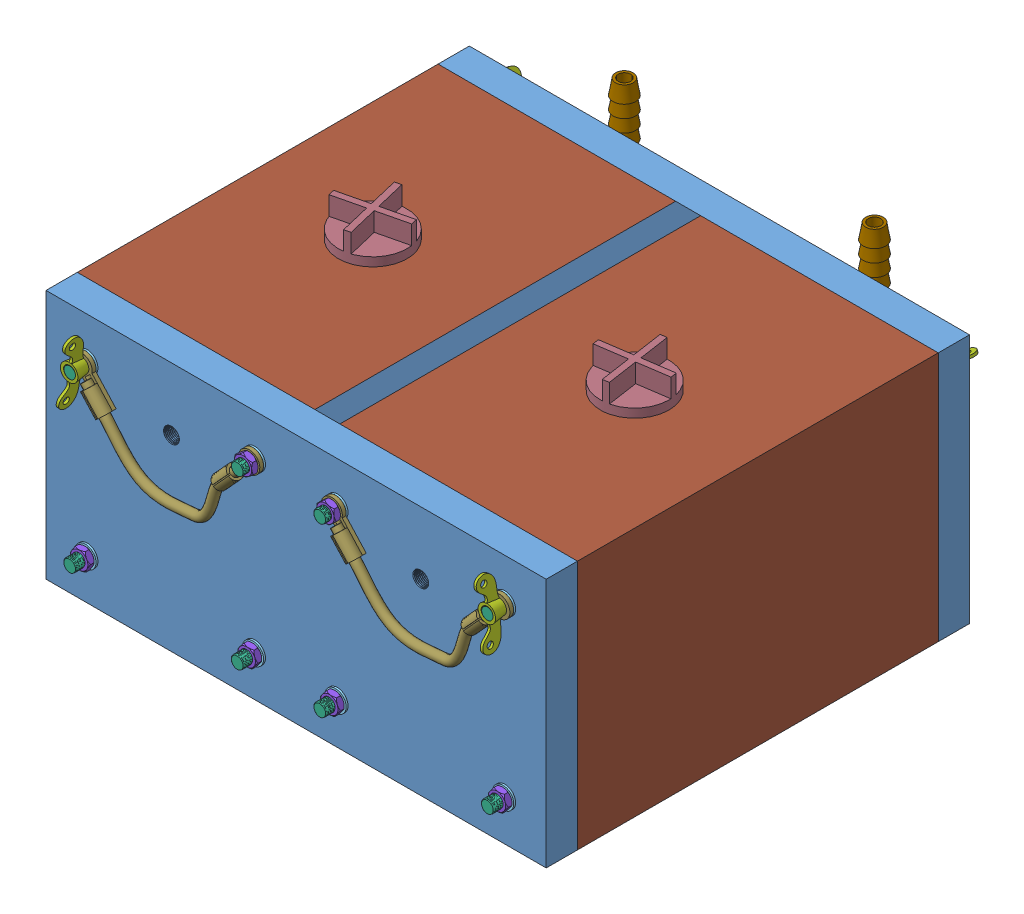
SolidWorks assembly Ventilator, configuration Default. Lengths in mm.
Overall size (400 222 393.22).
352 component instances, 13 part files, 106 mates.
Components (placement in the parent):
- Glass-1: Glass [Default] at (153.2199 -57.0551 297.1136) size (400 200 26.12)
- All Battery Block-1: All Battery Block [Default] at (-10.6585 129.0849 -81.5684) size (150 150 287)
  - Block Battery-1: Block Battery [Default] at (-175.922 -206.6429 -286.6039) size (150 150 40)
    - Gasket-12: Gasket [Default] at (244.3004 275.7985 390.286) size (150 150 3)
    - Plate-1-7: Plate-1 [Default] at (239.8004 279.4658 389.286) size (150 150 1)
    - Gasket-13: Gasket [Default] at (244.3004 275.7985 386.286) size (150 150 3)
    - Plate-1-8: Plate-1 [Default] at (239.8004 279.4658 385.286) size (150 150 1)
    - Gasket-14: Gasket [Default] at (244.3004 275.7985 382.286) size (150 150 3)
    - Plate-2-4: Plate-2 [Default] at (239.8004 279.4658 381.286) size (150 150 1)
    - Plate-1-10: Plate-1 [Default] at (239.8004 279.4658 393.286) size (150 150 1)
    - Gasket-16: Gasket [Default] at (244.3004 275.7985 394.286) size (150 150 3)
    - Plate-1-11: Plate-1 [Default] at (239.8004 279.4658 397.286) size (150 150 1)
    - Gasket-17: Gasket [Default] at (244.3004 275.7985 398.286) size (150 150 3)
    - Plate-2-5: Plate-2 [Default] at (239.8004 279.4658 402.286) x (-1 0 0) z (0 0 -1) size (150 150 1)
    - Gasket-18: Gasket [Default] at (244.3004 275.7985 402.286) size (150 150 3)
    - Plate-1-12: Plate-1 [Default] at (239.8004 279.4658 405.286) size (150 150 1)
    - Gasket-19: Gasket [Default] at (244.3004 275.7985 406.286) size (150 150 3)
    - Plate-1-13: Plate-1 [Default] at (239.8004 279.4658 409.286) size (150 150 1)
    - Gasket-20: Gasket [Default] at (244.3004 275.7985 410.286) size (150 150 3)
    - Plate-1-14: Plate-1 [Default] at (239.8004 279.4658 413.286) size (150 150 1)
    - Gasket-21: Gasket [Default] at (244.3004 275.7985 414.286) size (150 150 3)
    - Plate-1-15: Plate-1 [Default] at (239.8004 279.4658 417.286) size (150 150 1)
    - Gasket-22: Gasket [Default] at (244.3004 275.7985 418.286) size (150 150 3)
  - Block Battery-2: Block Battery [Default] at (-175.922 -206.6429 -246.6039) size (150 150 40)
    - Gasket-12: Gasket [Default] at (244.3004 275.7985 390.286) size (150 150 3)
    - Plate-1-7: Plate-1 [Default] at (239.8004 279.4658 389.286) size (150 150 1)
    - Gasket-13: Gasket [Default] at (244.3004 275.7985 386.286) size (150 150 3)
    - Plate-1-8: Plate-1 [Default] at (239.8004 279.4658 385.286) size (150 150 1)
    - Gasket-14: Gasket [Default] at (244.3004 275.7985 382.286) size (150 150 3)
    - Plate-2-4: Plate-2 [Default] at (239.8004 279.4658 381.286) size (150 150 1)
    - Plate-1-10: Plate-1 [Default] at (239.8004 279.4658 393.286) size (150 150 1)
    - Gasket-16: Gasket [Default] at (244.3004 275.7985 394.286) size (150 150 3)
    - Plate-1-11: Plate-1 [Default] at (239.8004 279.4658 397.286) size (150 150 1)
    - Gasket-17: Gasket [Default] at (244.3004 275.7985 398.286) size (150 150 3)
    - Plate-2-5: Plate-2 [Default] at (239.8004 279.4658 402.286) x (-1 0 0) z (0 0 -1) size (150 150 1)
    - Gasket-18: Gasket [Default] at (244.3004 275.7985 402.286) size (150 150 3)
    - Plate-1-12: Plate-1 [Default] at (239.8004 279.4658 405.286) size (150 150 1)
    - Gasket-19: Gasket [Default] at (244.3004 275.7985 406.286) size (150 150 3)
    - Plate-1-13: Plate-1 [Default] at (239.8004 279.4658 409.286) size (150 150 1)
    - Gasket-20: Gasket [Default] at (244.3004 275.7985 410.286) size (150 150 3)
    - Plate-1-14: Plate-1 [Default] at (239.8004 279.4658 413.286) size (150 150 1)
    - Gasket-21: Gasket [Default] at (244.3004 275.7985 414.286) size (150 150 3)
    - Plate-1-15: Plate-1 [Default] at (239.8004 279.4658 417.286) size (150 150 1)
    - Gasket-22: Gasket [Default] at (244.3004 275.7985 418.286) size (150 150 3)
  - Block Battery-3: Block Battery [Default] at (-175.922 -206.6429 -206.6039) size (150 150 40)
    - Gasket-12: Gasket [Default] at (244.3004 275.7985 390.286) size (150 150 3)
    - Plate-1-7: Plate-1 [Default] at (239.8004 279.4658 389.286) size (150 150 1)
    - Gasket-13: Gasket [Default] at (244.3004 275.7985 386.286) size (150 150 3)
    - Plate-1-8: Plate-1 [Default] at (239.8004 279.4658 385.286) size (150 150 1)
    - Gasket-14: Gasket [Default] at (244.3004 275.7985 382.286) size (150 150 3)
    - Plate-2-4: Plate-2 [Default] at (239.8004 279.4658 381.286) size (150 150 1)
    - Plate-1-10: Plate-1 [Default] at (239.8004 279.4658 393.286) size (150 150 1)
    - Gasket-16: Gasket [Default] at (244.3004 275.7985 394.286) size (150 150 3)
    - Plate-1-11: Plate-1 [Default] at (239.8004 279.4658 397.286) size (150 150 1)
    - Gasket-17: Gasket [Default] at (244.3004 275.7985 398.286) size (150 150 3)
    - Plate-2-5: Plate-2 [Default] at (239.8004 279.4658 402.286) x (-1 0 0) z (0 0 -1) size (150 150 1)
    - Gasket-18: Gasket [Default] at (244.3004 275.7985 402.286) size (150 150 3)
    - Plate-1-12: Plate-1 [Default] at (239.8004 279.4658 405.286) size (150 150 1)
    - Gasket-19: Gasket [Default] at (244.3004 275.7985 406.286) size (150 150 3)
    - Plate-1-13: Plate-1 [Default] at (239.8004 279.4658 409.286) size (150 150 1)
    - Gasket-20: Gasket [Default] at (244.3004 275.7985 410.286) size (150 150 3)
    - Plate-1-14: Plate-1 [Default] at (239.8004 279.4658 413.286) size (150 150 1)
    - Gasket-21: Gasket [Default] at (244.3004 275.7985 414.286) size (150 150 3)
    - Plate-1-15: Plate-1 [Default] at (239.8004 279.4658 417.286) size (150 150 1)
    - Gasket-22: Gasket [Default] at (244.3004 275.7985 418.286) size (150 150 3)
  - Block Battery-4: Block Battery [Default] at (-175.922 -206.6429 -166.6039) size (150 150 40)
    - Gasket-12: Gasket [Default] at (244.3004 275.7985 390.286) size (150 150 3)
    - Plate-1-7: Plate-1 [Default] at (239.8004 279.4658 389.286) size (150 150 1)
    - Gasket-13: Gasket [Default] at (244.3004 275.7985 386.286) size (150 150 3)
    - Plate-1-8: Plate-1 [Default] at (239.8004 279.4658 385.286) size (150 150 1)
    - Gasket-14: Gasket [Default] at (244.3004 275.7985 382.286) size (150 150 3)
    - Plate-2-4: Plate-2 [Default] at (239.8004 279.4658 381.286) size (150 150 1)
    - Plate-1-10: Plate-1 [Default] at (239.8004 279.4658 393.286) size (150 150 1)
    - Gasket-16: Gasket [Default] at (244.3004 275.7985 394.286) size (150 150 3)
    - Plate-1-11: Plate-1 [Default] at (239.8004 279.4658 397.286) size (150 150 1)
    - Gasket-17: Gasket [Default] at (244.3004 275.7985 398.286) size (150 150 3)
    - Plate-2-5: Plate-2 [Default] at (239.8004 279.4658 402.286) x (-1 0 0) z (0 0 -1) size (150 150 1)
    - Gasket-18: Gasket [Default] at (244.3004 275.7985 402.286) size (150 150 3)
    - Plate-1-12: Plate-1 [Default] at (239.8004 279.4658 405.286) size (150 150 1)
    - Gasket-19: Gasket [Default] at (244.3004 275.7985 406.286) size (150 150 3)
    - Plate-1-13: Plate-1 [Default] at (239.8004 279.4658 409.286) size (150 150 1)
    - Gasket-20: Gasket [Default] at (244.3004 275.7985 410.286) size (150 150 3)
    - Plate-1-14: Plate-1 [Default] at (239.8004 279.4658 413.286) size (150 150 1)
    - Gasket-21: Gasket [Default] at (244.3004 275.7985 414.286) size (150 150 3)
    - Plate-1-15: Plate-1 [Default] at (239.8004 279.4658 417.286) size (150 150 1)
    - Gasket-22: Gasket [Default] at (244.3004 275.7985 418.286) size (150 150 3)
  - Block Battery-5: Block Battery [Default] at (-175.922 -206.6429 -126.6039) size (150 150 40)
    - Gasket-12: Gasket [Default] at (244.3004 275.7985 390.286) size (150 150 3)
    - Plate-1-7: Plate-1 [Default] at (239.8004 279.4658 389.286) size (150 150 1)
    - Gasket-13: Gasket [Default] at (244.3004 275.7985 386.286) size (150 150 3)
    - Plate-1-8: Plate-1 [Default] at (239.8004 279.4658 385.286) size (150 150 1)
    - Gasket-14: Gasket [Default] at (244.3004 275.7985 382.286) size (150 150 3)
    - Plate-2-4: Plate-2 [Default] at (239.8004 279.4658 381.286) size (150 150 1)
    - Plate-1-10: Plate-1 [Default] at (239.8004 279.4658 393.286) size (150 150 1)
    - Gasket-16: Gasket [Default] at (244.3004 275.7985 394.286) size (150 150 3)
    - Plate-1-11: Plate-1 [Default] at (239.8004 279.4658 397.286) size (150 150 1)
    - Gasket-17: Gasket [Default] at (244.3004 275.7985 398.286) size (150 150 3)
    - Plate-2-5: Plate-2 [Default] at (239.8004 279.4658 402.286) x (-1 0 0) z (0 0 -1) size (150 150 1)
    - Gasket-18: Gasket [Default] at (244.3004 275.7985 402.286) size (150 150 3)
    - Plate-1-12: Plate-1 [Default] at (239.8004 279.4658 405.286) size (150 150 1)
    - Gasket-19: Gasket [Default] at (244.3004 275.7985 406.286) size (150 150 3)
    - Plate-1-13: Plate-1 [Default] at (239.8004 279.4658 409.286) size (150 150 1)
    - Gasket-20: Gasket [Default] at (244.3004 275.7985 410.286) size (150 150 3)
    - Plate-1-14: Plate-1 [Default] at (239.8004 279.4658 413.286) size (150 150 1)
    - Gasket-21: Gasket [Default] at (244.3004 275.7985 414.286) size (150 150 3)
    - Plate-1-15: Plate-1 [Default] at (239.8004 279.4658 417.286) size (150 150 1)
    - Gasket-22: Gasket [Default] at (244.3004 275.7985 418.286) size (150 150 3)
  - Block Battery-6: Block Battery [Default] at (-175.922 -206.6429 -86.6039) size (150 150 40)
    - Gasket-12: Gasket [Default] at (244.3004 275.7985 390.286) size (150 150 3)
    - Plate-1-7: Plate-1 [Default] at (239.8004 279.4658 389.286) size (150 150 1)
    - Gasket-13: Gasket [Default] at (244.3004 275.7985 386.286) size (150 150 3)
    - Plate-1-8: Plate-1 [Default] at (239.8004 279.4658 385.286) size (150 150 1)
    - Gasket-14: Gasket [Default] at (244.3004 275.7985 382.286) size (150 150 3)
    - Plate-2-4: Plate-2 [Default] at (239.8004 279.4658 381.286) size (150 150 1)
    - Plate-1-10: Plate-1 [Default] at (239.8004 279.4658 393.286) size (150 150 1)
    - Gasket-16: Gasket [Default] at (244.3004 275.7985 394.286) size (150 150 3)
    - Plate-1-11: Plate-1 [Default] at (239.8004 279.4658 397.286) size (150 150 1)
    - Gasket-17: Gasket [Default] at (244.3004 275.7985 398.286) size (150 150 3)
    - Plate-2-5: Plate-2 [Default] at (239.8004 279.4658 402.286) x (-1 0 0) z (0 0 -1) size (150 150 1)
    - Gasket-18: Gasket [Default] at (244.3004 275.7985 402.286) size (150 150 3)
    - Plate-1-12: Plate-1 [Default] at (239.8004 279.4658 405.286) size (150 150 1)
    - Gasket-19: Gasket [Default] at (244.3004 275.7985 406.286) size (150 150 3)
    - Plate-1-13: Plate-1 [Default] at (239.8004 279.4658 409.286) size (150 150 1)
    - Gasket-20: Gasket [Default] at (244.3004 275.7985 410.286) size (150 150 3)
    - Plate-1-14: Plate-1 [Default] at (239.8004 279.4658 413.286) size (150 150 1)
    - Gasket-21: Gasket [Default] at (244.3004 275.7985 414.286) size (150 150 3)
    - Plate-1-15: Plate-1 [Default] at (239.8004 279.4658 417.286) size (150 150 1)
    - Gasket-22: Gasket [Default] at (244.3004 275.7985 418.286) size (150 150 3)
  - Block Battery-7: Block Battery [Default] at (-175.922 -206.6429 -46.6039) size (150 150 40)
    - Gasket-12: Gasket [Default] at (244.3004 275.7985 390.286) size (150 150 3)
    - Plate-1-7: Plate-1 [Default] at (239.8004 279.4658 389.286) size (150 150 1)
    - Gasket-13: Gasket [Default] at (244.3004 275.7985 386.286) size (150 150 3)
    - Plate-1-8: Plate-1 [Default] at (239.8004 279.4658 385.286) size (150 150 1)
    - Gasket-14: Gasket [Default] at (244.3004 275.7985 382.286) size (150 150 3)
    - Plate-2-4: Plate-2 [Default] at (239.8004 279.4658 381.286) size (150 150 1)
    - Plate-1-10: Plate-1 [Default] at (239.8004 279.4658 393.286) size (150 150 1)
    - Gasket-16: Gasket [Default] at (244.3004 275.7985 394.286) size (150 150 3)
    - Plate-1-11: Plate-1 [Default] at (239.8004 279.4658 397.286) size (150 150 1)
    - Gasket-17: Gasket [Default] at (244.3004 275.7985 398.286) size (150 150 3)
    - Plate-2-5: Plate-2 [Default] at (239.8004 279.4658 402.286) x (-1 0 0) z (0 0 -1) size (150 150 1)
    - Gasket-18: Gasket [Default] at (244.3004 275.7985 402.286) size (150 150 3)
    - Plate-1-12: Plate-1 [Default] at (239.8004 279.4658 405.286) size (150 150 1)
    - Gasket-19: Gasket [Default] at (244.3004 275.7985 406.286) size (150 150 3)
    - Plate-1-13: Plate-1 [Default] at (239.8004 279.4658 409.286) size (150 150 1)
    - Gasket-20: Gasket [Default] at (244.3004 275.7985 410.286) size (150 150 3)
    - Plate-1-14: Plate-1 [Default] at (239.8004 279.4658 413.286) size (150 150 1)
    - Gasket-21: Gasket [Default] at (244.3004 275.7985 414.286) size (150 150 3)
    - Plate-1-15: Plate-1 [Default] at (239.8004 279.4658 417.286) size (150 150 1)
    - Gasket-22: Gasket [Default] at (244.3004 275.7985 418.286) size (150 150 3)
  - Plate-2-1: Plate-2 [Default] at (63.8784 72.8229 374.682) size (150 150 1)
  - Gasket-1: Gasket [Default] at (68.3784 69.1556 375.682) size (150 150 3)
  - Gasket-2: Gasket [Default] at (68.3784 69.1556 91.682) size (150 150 3)
- All Battery Block-2: All Battery Block [Default] at (189.3415 129.0849 -81.5684) size (150 150 287)
  - Block Battery-1: Block Battery [Default] at (-175.922 -206.6429 -286.6039) size (150 150 40)
    - Gasket-12: Gasket [Default] at (244.3004 275.7985 390.286) size (150 150 3)
    - Plate-1-7: Plate-1 [Default] at (239.8004 279.4658 389.286) size (150 150 1)
    - Gasket-13: Gasket [Default] at (244.3004 275.7985 386.286) size (150 150 3)
    - Plate-1-8: Plate-1 [Default] at (239.8004 279.4658 385.286) size (150 150 1)
    - Gasket-14: Gasket [Default] at (244.3004 275.7985 382.286) size (150 150 3)
    - Plate-2-4: Plate-2 [Default] at (239.8004 279.4658 381.286) size (150 150 1)
    - Plate-1-10: Plate-1 [Default] at (239.8004 279.4658 393.286) size (150 150 1)
    - Gasket-16: Gasket [Default] at (244.3004 275.7985 394.286) size (150 150 3)
    - Plate-1-11: Plate-1 [Default] at (239.8004 279.4658 397.286) size (150 150 1)
    - Gasket-17: Gasket [Default] at (244.3004 275.7985 398.286) size (150 150 3)
    - Plate-2-5: Plate-2 [Default] at (239.8004 279.4658 402.286) x (-1 0 0) z (0 0 -1) size (150 150 1)
    - Gasket-18: Gasket [Default] at (244.3004 275.7985 402.286) size (150 150 3)
    - Plate-1-12: Plate-1 [Default] at (239.8004 279.4658 405.286) size (150 150 1)
    - Gasket-19: Gasket [Default] at (244.3004 275.7985 406.286) size (150 150 3)
    - Plate-1-13: Plate-1 [Default] at (239.8004 279.4658 409.286) size (150 150 1)
    - Gasket-20: Gasket [Default] at (244.3004 275.7985 410.286) size (150 150 3)
    - Plate-1-14: Plate-1 [Default] at (239.8004 279.4658 413.286) size (150 150 1)
    - Gasket-21: Gasket [Default] at (244.3004 275.7985 414.286) size (150 150 3)
    - Plate-1-15: Plate-1 [Default] at (239.8004 279.4658 417.286) size (150 150 1)
    - Gasket-22: Gasket [Default] at (244.3004 275.7985 418.286) size (150 150 3)
  - Block Battery-2: Block Battery [Default] at (-175.922 -206.6429 -246.6039) size (150 150 40)
    - Gasket-12: Gasket [Default] at (244.3004 275.7985 390.286) size (150 150 3)
    - Plate-1-7: Plate-1 [Default] at (239.8004 279.4658 389.286) size (150 150 1)
    - Gasket-13: Gasket [Default] at (244.3004 275.7985 386.286) size (150 150 3)
    - Plate-1-8: Plate-1 [Default] at (239.8004 279.4658 385.286) size (150 150 1)
    - Gasket-14: Gasket [Default] at (244.3004 275.7985 382.286) size (150 150 3)
    - Plate-2-4: Plate-2 [Default] at (239.8004 279.4658 381.286) size (150 150 1)
    - Plate-1-10: Plate-1 [Default] at (239.8004 279.4658 393.286) size (150 150 1)
    - Gasket-16: Gasket [Default] at (244.3004 275.7985 394.286) size (150 150 3)
    - Plate-1-11: Plate-1 [Default] at (239.8004 279.4658 397.286) size (150 150 1)
    - Gasket-17: Gasket [Default] at (244.3004 275.7985 398.286) size (150 150 3)
    - Plate-2-5: Plate-2 [Default] at (239.8004 279.4658 402.286) x (-1 0 0) z (0 0 -1) size (150 150 1)
    - Gasket-18: Gasket [Default] at (244.3004 275.7985 402.286) size (150 150 3)
    - Plate-1-12: Plate-1 [Default] at (239.8004 279.4658 405.286) size (150 150 1)
    - Gasket-19: Gasket [Default] at (244.3004 275.7985 406.286) size (150 150 3)
    - Plate-1-13: Plate-1 [Default] at (239.8004 279.4658 409.286) size (150 150 1)
    - Gasket-20: Gasket [Default] at (244.3004 275.7985 410.286) size (150 150 3)
    - Plate-1-14: Plate-1 [Default] at (239.8004 279.4658 413.286) size (150 150 1)
    - Gasket-21: Gasket [Default] at (244.3004 275.7985 414.286) size (150 150 3)
    - Plate-1-15: Plate-1 [Default] at (239.8004 279.4658 417.286) size (150 150 1)
    - Gasket-22: Gasket [Default] at (244.3004 275.7985 418.286) size (150 150 3)
  - Block Battery-3: Block Battery [Default] at (-175.922 -206.6429 -206.6039) size (150 150 40)
    - Gasket-12: Gasket [Default] at (244.3004 275.7985 390.286) size (150 150 3)
    - Plate-1-7: Plate-1 [Default] at (239.8004 279.4658 389.286) size (150 150 1)
    - Gasket-13: Gasket [Default] at (244.3004 275.7985 386.286) size (150 150 3)
    - Plate-1-8: Plate-1 [Default] at (239.8004 279.4658 385.286) size (150 150 1)
    - Gasket-14: Gasket [Default] at (244.3004 275.7985 382.286) size (150 150 3)
    - Plate-2-4: Plate-2 [Default] at (239.8004 279.4658 381.286) size (150 150 1)
    - Plate-1-10: Plate-1 [Default] at (239.8004 279.4658 393.286) size (150 150 1)
    - Gasket-16: Gasket [Default] at (244.3004 275.7985 394.286) size (150 150 3)
    - Plate-1-11: Plate-1 [Default] at (239.8004 279.4658 397.286) size (150 150 1)
    - Gasket-17: Gasket [Default] at (244.3004 275.7985 398.286) size (150 150 3)
    - Plate-2-5: Plate-2 [Default] at (239.8004 279.4658 402.286) x (-1 0 0) z (0 0 -1) size (150 150 1)
    - Gasket-18: Gasket [Default] at (244.3004 275.7985 402.286) size (150 150 3)
    - Plate-1-12: Plate-1 [Default] at (239.8004 279.4658 405.286) size (150 150 1)
    - Gasket-19: Gasket [Default] at (244.3004 275.7985 406.286) size (150 150 3)
    - Plate-1-13: Plate-1 [Default] at (239.8004 279.4658 409.286) size (150 150 1)
    - Gasket-20: Gasket [Default] at (244.3004 275.7985 410.286) size (150 150 3)
    - Plate-1-14: Plate-1 [Default] at (239.8004 279.4658 413.286) size (150 150 1)
    - Gasket-21: Gasket [Default] at (244.3004 275.7985 414.286) size (150 150 3)
    - Plate-1-15: Plate-1 [Default] at (239.8004 279.4658 417.286) size (150 150 1)
    - Gasket-22: Gasket [Default] at (244.3004 275.7985 418.286) size (150 150 3)
  - Block Battery-4: Block Battery [Default] at (-175.922 -206.6429 -166.6039) size (150 150 40)
    - Gasket-12: Gasket [Default] at (244.3004 275.7985 390.286) size (150 150 3)
    - Plate-1-7: Plate-1 [Default] at (239.8004 279.4658 389.286) size (150 150 1)
    - Gasket-13: Gasket [Default] at (244.3004 275.7985 386.286) size (150 150 3)
    - Plate-1-8: Plate-1 [Default] at (239.8004 279.4658 385.286) size (150 150 1)
    - Gasket-14: Gasket [Default] at (244.3004 275.7985 382.286) size (150 150 3)
    - Plate-2-4: Plate-2 [Default] at (239.8004 279.4658 381.286) size (150 150 1)
    - Plate-1-10: Plate-1 [Default] at (239.8004 279.4658 393.286) size (150 150 1)
    - Gasket-16: Gasket [Default] at (244.3004 275.7985 394.286) size (150 150 3)
    - Plate-1-11: Plate-1 [Default] at (239.8004 279.4658 397.286) size (150 150 1)
    - Gasket-17: Gasket [Default] at (244.3004 275.7985 398.286) size (150 150 3)
    - Plate-2-5: Plate-2 [Default] at (239.8004 279.4658 402.286) x (-1 0 0) z (0 0 -1) size (150 150 1)
    - Gasket-18: Gasket [Default] at (244.3004 275.7985 402.286) size (150 150 3)
    - Plate-1-12: Plate-1 [Default] at (239.8004 279.4658 405.286) size (150 150 1)
    - Gasket-19: Gasket [Default] at (244.3004 275.7985 406.286) size (150 150 3)
    - Plate-1-13: Plate-1 [Default] at (239.8004 279.4658 409.286) size (150 150 1)
    - Gasket-20: Gasket [Default] at (244.3004 275.7985 410.286) size (150 150 3)
    - Plate-1-14: Plate-1 [Default] at (239.8004 279.4658 413.286) size (150 150 1)
    - Gasket-21: Gasket [Default] at (244.3004 275.7985 414.286) size (150 150 3)
    - Plate-1-15: Plate-1 [Default] at (239.8004 279.4658 417.286) size (150 150 1)
    - Gasket-22: Gasket [Default] at (244.3004 275.7985 418.286) size (150 150 3)
  - Block Battery-5: Block Battery [Default] at (-175.922 -206.6429 -126.6039) size (150 150 40)
    - Gasket-12: Gasket [Default] at (244.3004 275.7985 390.286) size (150 150 3)
    - Plate-1-7: Plate-1 [Default] at (239.8004 279.4658 389.286) size (150 150 1)
    - Gasket-13: Gasket [Default] at (244.3004 275.7985 386.286) size (150 150 3)
    - Plate-1-8: Plate-1 [Default] at (239.8004 279.4658 385.286) size (150 150 1)
    - Gasket-14: Gasket [Default] at (244.3004 275.7985 382.286) size (150 150 3)
    - Plate-2-4: Plate-2 [Default] at (239.8004 279.4658 381.286) size (150 150 1)
    - Plate-1-10: Plate-1 [Default] at (239.8004 279.4658 393.286) size (150 150 1)
    - Gasket-16: Gasket [Default] at (244.3004 275.7985 394.286) size (150 150 3)
    - Plate-1-11: Plate-1 [Default] at (239.8004 279.4658 397.286) size (150 150 1)
    - Gasket-17: Gasket [Default] at (244.3004 275.7985 398.286) size (150 150 3)
    - Plate-2-5: Plate-2 [Default] at (239.8004 279.4658 402.286) x (-1 0 0) z (0 0 -1) size (150 150 1)
    - Gasket-18: Gasket [Default] at (244.3004 275.7985 402.286) size (150 150 3)
    - Plate-1-12: Plate-1 [Default] at (239.8004 279.4658 405.286) size (150 150 1)
    - Gasket-19: Gasket [Default] at (244.3004 275.7985 406.286) size (150 150 3)
    - Plate-1-13: Plate-1 [Default] at (239.8004 279.4658 409.286) size (150 150 1)
    - Gasket-20: Gasket [Default] at (244.3004 275.7985 410.286) size (150 150 3)
    - Plate-1-14: Plate-1 [Default] at (239.8004 279.4658 413.286) size (150 150 1)
    - Gasket-21: Gasket [Default] at (244.3004 275.7985 414.286) size (150 150 3)
    - Plate-1-15: Plate-1 [Default] at (239.8004 279.4658 417.286) size (150 150 1)
    - Gasket-22: Gasket [Default] at (244.3004 275.7985 418.286) size (150 150 3)
  - Block Battery-6: Block Battery [Default] at (-175.922 -206.6429 -86.6039) size (150 150 40)
    - Gasket-12: Gasket [Default] at (244.3004 275.7985 390.286) size (150 150 3)
    - Plate-1-7: Plate-1 [Default] at (239.8004 279.4658 389.286) size (150 150 1)
    - Gasket-13: Gasket [Default] at (244.3004 275.7985 386.286) size (150 150 3)
    - Plate-1-8: Plate-1 [Default] at (239.8004 279.4658 385.286) size (150 150 1)
    - Gasket-14: Gasket [Default] at (244.3004 275.7985 382.286) size (150 150 3)
    - Plate-2-4: Plate-2 [Default] at (239.8004 279.4658 381.286) size (150 150 1)
    - Plate-1-10: Plate-1 [Default] at (239.8004 279.4658 393.286) size (150 150 1)
    - Gasket-16: Gasket [Default] at (244.3004 275.7985 394.286) size (150 150 3)
    - Plate-1-11: Plate-1 [Default] at (239.8004 279.4658 397.286) size (150 150 1)
    - Gasket-17: Gasket [Default] at (244.3004 275.7985 398.286) size (150 150 3)
    - Plate-2-5: Plate-2 [Default] at (239.8004 279.4658 402.286) x (-1 0 0) z (0 0 -1) size (150 150 1)
    - Gasket-18: Gasket [Default] at (244.3004 275.7985 402.286) size (150 150 3)
    - Plate-1-12: Plate-1 [Default] at (239.8004 279.4658 405.286) size (150 150 1)
    - Gasket-19: Gasket [Default] at (244.3004 275.7985 406.286) size (150 150 3)
    - Plate-1-13: Plate-1 [Default] at (239.8004 279.4658 409.286) size (150 150 1)
    - Gasket-20: Gasket [Default] at (244.3004 275.7985 410.286) size (150 150 3)
    - Plate-1-14: Plate-1 [Default] at (239.8004 279.4658 413.286) size (150 150 1)
    - Gasket-21: Gasket [Default] at (244.3004 275.7985 414.286) size (150 150 3)
    - Plate-1-15: Plate-1 [Default] at (239.8004 279.4658 417.286) size (150 150 1)
    - Gasket-22: Gasket [Default] at (244.3004 275.7985 418.286) size (150 150 3)
  - Block Battery-7: Block Battery [Default] at (-175.922 -206.6429 -46.6039) size (150 150 40)
    - Gasket-12: Gasket [Default] at (244.3004 275.7985 390.286) size (150 150 3)
    - Plate-1-7: Plate-1 [Default] at (239.8004 279.4658 389.286) size (150 150 1)
    - Gasket-13: Gasket [Default] at (244.3004 275.7985 386.286) size (150 150 3)
    - Plate-1-8: Plate-1 [Default] at (239.8004 279.4658 385.286) size (150 150 1)
    - Gasket-14: Gasket [Default] at (244.3004 275.7985 382.286) size (150 150 3)
    - Plate-2-4: Plate-2 [Default] at (239.8004 279.4658 381.286) size (150 150 1)
    - Plate-1-10: Plate-1 [Default] at (239.8004 279.4658 393.286) size (150 150 1)
    - Gasket-16: Gasket [Default] at (244.3004 275.7985 394.286) size (150 150 3)
    - Plate-1-11: Plate-1 [Default] at (239.8004 279.4658 397.286) size (150 150 1)
    - Gasket-17: Gasket [Default] at (244.3004 275.7985 398.286) size (150 150 3)
    - Plate-2-5: Plate-2 [Default] at (239.8004 279.4658 402.286) x (-1 0 0) z (0 0 -1) size (150 150 1)
    - Gasket-18: Gasket [Default] at (244.3004 275.7985 402.286) size (150 150 3)
    - Plate-1-12: Plate-1 [Default] at (239.8004 279.4658 405.286) size (150 150 1)
    - Gasket-19: Gasket [Default] at (244.3004 275.7985 406.286) size (150 150 3)
    - Plate-1-13: Plate-1 [Default] at (239.8004 279.4658 409.286) size (150 150 1)
    - Gasket-20: Gasket [Default] at (244.3004 275.7985 410.286) size (150 150 3)
    - Plate-1-14: Plate-1 [Default] at (239.8004 279.4658 413.286) size (150 150 1)
    - Gasket-21: Gasket [Default] at (244.3004 275.7985 414.286) size (150 150 3)
    - Plate-1-15: Plate-1 [Default] at (239.8004 279.4658 417.286) size (150 150 1)
    - Gasket-22: Gasket [Default] at (244.3004 275.7985 418.286) size (150 150 3)
  - Plate-2-1: Plate-2 [Default] at (63.8784 72.8229 374.682) size (150 150 1)
  - Gasket-1: Gasket [Default] at (68.3784 69.1556 375.682) size (150 150 3)
  - Gasket-2: Gasket [Default] at (68.3784 69.1556 91.682) size (150 150 3)
- Glass-2: Glass [Default] at (153.2199 -57.0551 -16.3864) size (400 200 26.12)
- Washer-1: Washer [Default] at (320.2199 268.9078 -17.8864) size (17 17 1.5)
- Screw-2: Screw [Default] at (-13.7801 268.9078 -30.3864) size (10.01 10.25 367.6)
- Washer-2: Washer [Default] at (-13.7801 268.9078 322.1136) size (17 17 1.5)
- Vint-3: Vint [Default] at (320.2199 268.9078 -27.8864) x (0.941946 0.335764 0) z (0 0 1) size (52.29 14 17.39)
- Washer-3: Washer [Default] at (-13.7801 268.9078 -17.8864) size (17 17 1.5)
- Screw-4: Screw [Default] at (-13.7801 134.9078 -30.3864) size (10.01 10.25 367.6)
- Screw-5: Screw [Default] at (120.2199 268.9078 -30.3864) size (10.01 10.25 367.6)
- Washer-4: Washer [Default] at (120.2199 268.9078 322.1136) size (17 17 1.5)
- Washer-5: Washer [Default] at (-13.7801 134.9078 322.1136) size (17 17 1.5)
- Washer-6: Washer [Default] at (120.2199 268.9078 -17.8864) size (17 17 1.5)
- Washer-7: Washer [Default] at (-13.7801 134.9078 -17.8864) size (17 17 1.5)
- Screw-6: Screw [Default] at (186.2199 268.9078 -30.3864) size (10.01 10.25 367.6)
- Washer-8: Washer [Default] at (186.2199 268.9078 -17.8864) size (17 17 1.5)
- Screw-7: Screw [Default] at (320.2199 268.9078 -30.3864) size (10.01 10.25 367.6)
- Screw-8: Screw [Default] at (320.2199 134.9078 -30.3864) size (10.01 10.25 367.6)
- Screw-9: Screw [Default] at (186.2199 134.9078 -30.3864) size (10.01 10.25 367.6)
- Screw-10: Screw [Default] at (120.2199 134.9078 -30.3864) size (10.01 10.25 367.6)
- Washer-9: Washer [Default] at (320.2199 268.9078 322.1136) size (17 17 1.5)
- Washer-10: Washer [Default] at (320.2199 134.9078 322.1136) size (17 17 1.5)
- Washer-11: Washer [Default] at (186.2199 268.9078 322.1136) size (17 17 1.5)
- Washer-12: Washer [Default] at (186.2199 134.9078 322.1136) size (17 17 1.5)
- Washer-13: Washer [Default] at (120.2199 134.9078 322.1136) size (17 17 1.5)
- Washer-14: Washer [Default] at (320.2199 134.9078 -17.8864) size (17 17 1.5)
- Washer-15: Washer [Default] at (120.2199 134.9078 -17.8864) size (17 17 1.5)
- Washer-16: Washer [Default] at (186.2199 134.9078 -17.8864) size (17 17 1.5)
- Vint-5: Vint [Default] at (-13.7801 268.9078 -27.8864) x (0.551468 -0.834196 0) z (0 0 1) size (52.29 14 17.39)
- Mutter M10-2: Mutter M10 [Default] at (120.2199 268.9078 -22.8864) size (16.8 16.24 6.22)
- Mutter M10-4: Mutter M10 [Default] at (120.2199 134.9078 323.6136) size (16.8 16.24 6.22)
- Mutter M10-5: Mutter M10 [Default] at (186.2199 134.9078 323.6136) size (16.8 16.24 6.22)
- Mutter M10-6: Mutter M10 [Default] at (186.2199 134.9078 -22.8864) size (16.8 16.24 6.22)
- Mutter M10-7: Mutter M10 [Default] at (186.2199 268.9078 -22.8864) size (16.8 16.24 6.22)
- Mutter M10-8: Mutter M10 [Default] at (120.2199 134.9078 -22.8864) size (16.8 16.24 6.22)
- branch pipe-1: branch pipe [Default] at (53.2199 251.9078 -32.3864) x (-1 0 0) z (0 0 1) size (18.58 74 52.8)
- branch pipe-2: branch pipe [Default] at (253.2199 251.9078 -32.3864) x (-1 0 0) z (0 0 1) size (18.58 74 52.8)
- Partition Plate 288,5x200x20-1: Partition Plate 288,5x200x20 [Default] at (153.2199 301.9078 8.6136) size (20 200 288.5)
- Cube Close-1: Cube Close [Default] at (152.9608 202.0373 8.6136) size (400 200.96 288.5)
- Vint-12: Vint [Default] at (-13.7801 268.9078 336.6136) x (0.123933 0.992291 0) z (0 0 -1) size (52.29 14 17.39)
- Mutter M10-11: Mutter M10 [Default] at (-13.7801 134.9078 323.6136) x (0.987802 0.155716 0) z (0 0 1) size (16.8 16.24 6.22)
- Mutter M10-12: Mutter M10 [Default] at (320.2199 134.9078 323.4893) x (0.999966 0.00828 0) z (0 0 1) size (16.8 16.24 6.22)
- Mutter M10-13: Mutter M10 [Default] at (-13.7801 134.9078 -22.8574) x (0.66302 0.748602 0) z (0 0 1) size (16.8 16.24 6.22)
- Mutter M10-14: Mutter M10 [Default] at (320.2199 134.9078 -22.8876) x (0.969572 0.244807 0) z (0 0 1) size (16.8 16.24 6.22)
- Vint-13: Vint [Default] at (320.2199 268.9078 336.6136) x (-0.128135 0.991757 0) z (0 0 -1) size (52.29 14 17.39)
- Bridge-3: Bridge [Default] at (253.2199 268.9078 323.6136) size (151 69.64 11.31)
- Mutter M10-17: Mutter M10 [Default] at (186.2199 268.9078 326.6732) x (0.322455 -0.946585 0) z (0 0 1) size (16.8 16.24 6.22)
- Bridge-4: Bridge [Default] at (53.2199 268.9078 323.6136) size (151 69.64 11.31)
- Mutter M10-18: Mutter M10 [Default] at (120.2199 268.9078 326.6136) x (-0.738179 -0.674605 0) z (0 0 1) size (16.8 16.24 6.22)
- Plug-1: Plug [Default] at (257.7018 281.9078 155.8328) x (0.98923 0 -0.146369) z (0.146369 0 0.98923) size (55 43.3 55)
- Plug-2: Plug [Default] at (48.2199 281.9078 155.8328) x (-0.232941 0 -0.972491) z (0.972491 0 -0.232941) size (55 43.3 55)
Mates (geometry in assembly coordinates):
- Concentric1: concentric: circle of Glass-1; circle of All Battery Block-1/Plate-2-1
- Distance1: distance = 0 mm: plane of All Battery Block-1/Gasket-1 through (57.7199 198.2405 297.1136) normal (0 0 1); plane of Glass-1 through (153.2199 -57.0551 297.1136) normal (0 0 -1)
- Parallel1: parallel: line of Glass-1 through (-46.7801 101.9078 297.1136) axis (1 0 0); line of All Battery Block-1/Gasket-1 through (3.2199 126.9078 294.1136) axis (1 0 0)
- Concentric2: concentric: circle of Glass-1; circle of All Battery Block-2/Plate-2-1
- Distance2: distance = 0 mm: plane of All Battery Block-2/Gasket-1 through (257.7199 198.2405 297.1136) normal (0 0 1); plane of Glass-1 through (153.2199 -57.0551 297.1136) normal (0 0 -1)
- Parallel2: parallel: line of Glass-1 through (-46.7801 101.9078 297.1136) axis (1 0 0); line of All Battery Block-2/Gasket-1 through (203.2199 126.9078 297.1136) axis (1 0 0)
- Parallel3: parallel: line of Glass-1 through (-46.7801 101.9078 297.1136) axis (1 0 0); line of All Battery Block-2/Gasket-1 through (203.2199 126.9078 297.1136) axis (1 0 0)
- Concentric3: concentric: circle of All Battery Block-2/Block Battery-1/Plate-2-4; circle of Glass-2
- Concentric4: concentric: circle of Glass-1; circle of Glass-2
- Concentric6: concentric: cylinder of Glass-1 through (-13.7801 268.9078 322.1136) axis (0 0 -1) radius 5; cylinder of Screw-2 through (-13.7801 268.9078 336.1136) axis (0 0 -1) radius 5
- Distance7: distance = 14 mm: plane of Screw-2 through (-13.7801 268.9078 336.1136) normal (0 0 1); line of Glass-1 through (353.2199 301.9078 322.1136) axis (-1 0 0)
- Concentric7: concentric: cylinder of Screw-2 through (-13.7801 268.9078 336.1136) axis (0 0 -1) radius 5; circle of Washer-2
- Distance10: distance = 25 mm: plane of Washer-2 through (-13.7801 268.9078 322.1136) normal (0 0 -1); plane of Glass-1 through (153.2199 -57.0551 297.1136) normal (0 0 -1)
- Concentric9: concentric: cylinder of Screw-2 through (-13.7801 268.9078 336.1136) axis (0 0 -1) radius 5; circle of Washer-3
- Distance11: distance = 0 mm: plane of Washer-3 through (-13.7801 268.9078 -16.3864) normal (0 0 1); plane of Glass-2 through (153.2199 -57.0551 -16.3864) normal (0 0 -1)
- Concentric10: concentric: cylinder of Glass-1 through (-13.7801 134.9078 322.1136) axis (0 0 -1) radius 5; cylinder of Screw-4 through (-13.7801 134.9078 336.1136) axis (0 0 -1) radius 5
- Distance12: distance = 14 mm: plane of Screw-4 through (-13.7801 134.9078 336.1136) normal (0 0 1); line of Glass-1 through (-46.7801 101.9078 322.1136) axis (1 0 0)
- Concentric11: concentric: cylinder of Glass-1 through (120.2199 268.9078 322.1136) axis (0 0 -1) radius 5; cylinder of Screw-5 through (120.2199 268.9078 336.1136) axis (0 0 -1) radius 5
- Distance13: distance = 14 mm: plane of Screw-5 through (120.2199 268.9078 -30.3864) normal (0 0 -1); plane of Glass-2 through (153.2199 -57.0551 -16.3864) normal (0 0 -1)
- Concentric12: concentric: cylinder of Screw-4 through (-13.7801 134.9078 336.1136) axis (0 0 -1) radius 5; circle of Washer-5
- Parallel5: parallel: plane of Glass-1 through (153.2199 -57.0551 297.1136) normal (0 0 -1); plane of Washer-5 through (-13.7801 134.9078 323.6136) normal (0 0 1)
- Distance15: distance = 25 mm: plane of Washer-5 through (-13.7801 134.9078 322.1136) normal (0 0 -1); plane of Glass-1 through (153.2199 -57.0551 297.1136) normal (0 0 -1)
- Distance16: distance = 39 mm: plane of Screw-5 through (120.2199 268.9078 336.1136) normal (0 0 1); plane of Glass-1 through (153.2199 -57.0551 297.1136) normal (0 0 -1)
- Concentric13: concentric: cylinder of Screw-5 through (120.2199 268.9078 336.1136) axis (0 0 -1) radius 5; circle of Washer-4
- Distance17: distance = 25 mm: plane of Washer-4 through (120.2199 268.9078 322.1136) normal (0 0 -1); plane of Glass-1 through (153.2199 -57.0551 297.1136) normal (0 0 -1)
- Concentric14: concentric: cylinder of Screw-4 through (-13.7801 134.9078 336.1136) axis (0 0 -1) radius 5; circle of Washer-7
- Distance18: distance = 0 mm: plane of Washer-7 through (-13.7801 134.9078 -16.3864) normal (0 0 1); plane of Glass-2 through (153.2199 -57.0551 -16.3864) normal (0 0 -1)
- Concentric15: concentric: cylinder of Screw-5 through (120.2199 268.9078 336.1136) axis (0 0 -1) radius 5; circle of Washer-6
- Distance19: distance = 0 mm: plane of Washer-6 through (120.2199 268.9078 -16.3864) normal (0 0 1); plane of Glass-2 through (153.2199 -57.0551 -16.3864) normal (0 0 -1)
- Concentric16: concentric: cylinder of Glass-2 through (186.2199 268.9078 8.6136) axis (0 0 -1) radius 5; cylinder of Screw-6 through (186.2199 268.9078 336.1136) axis (0 0 -1) radius 5
- Distance20: distance = 14 mm: plane of Screw-6 through (186.2199 268.9078 -30.3864) normal (0 0 -1); plane of Glass-2 through (153.2199 -57.0551 -16.3864) normal (0 0 -1)
- Concentric17: concentric: cylinder of Screw-6 through (186.2199 268.9078 336.1136) axis (0 0 -1) radius 5; circle of Washer-8
- Distance21: distance = 0 mm: plane of Washer-8 through (186.2199 268.9078 -16.3864) normal (0 0 1); plane of Glass-2 through (153.2199 -57.0551 -16.3864) normal (0 0 -1)
- Concentric18: concentric: cylinder of Glass-2 through (320.2199 268.9078 8.6136) axis (0 0 -1) radius 5; cylinder of Screw-7 through (320.2199 268.9078 336.1136) axis (0 0 -1) radius 5
- Distance22: distance = 14 mm: plane of Screw-7 through (320.2199 268.9078 -30.3864) normal (0 0 -1); plane of Glass-2 through (153.2199 -57.0551 -16.3864) normal (0 0 -1)
- Concentric19: concentric: cylinder of Glass-2 through (120.2199 134.9078 8.6136) axis (0 0 -1) radius 5; cylinder of Screw-10 through (120.2199 134.9078 336.1136) axis (0 0 -1) radius 5
- Concentric20: concentric: circle of Glass-2; cylinder of Screw-9 through (186.2199 134.9078 336.1136) axis (0 0 -1) radius 5
- Concentric21: concentric: cylinder of Glass-2 through (320.2199 134.9078 8.6136) axis (0 0 -1) radius 5; cylinder of Screw-8 through (320.2199 134.9078 336.1136) axis (0 0 -1) radius 5
- Distance23: distance = 14 mm: plane of Screw-10 through (120.2199 134.9078 -30.3864) normal (0 0 -1); plane of Glass-2 through (153.2199 -57.0551 -16.3864) normal (0 0 -1)
- Distance24: distance = 14 mm: plane of Screw-9 through (186.2199 134.9078 -30.3864) normal (0 0 -1); plane of Glass-2 through (153.2199 -57.0551 -16.3864) normal (0 0 -1)
- Distance25: distance = 14 mm: plane of Screw-8 through (320.2199 134.9078 -30.3864) normal (0 0 -1); plane of Glass-2 through (153.2199 -57.0551 -16.3864) normal (0 0 -1)
- Concentric22: concentric: cylinder of Screw-9 through (186.2199 134.9078 336.1136) axis (0 0 -1) radius 5; circle of Washer-12
- Distance26: distance = 25 mm: plane of Washer-12 through (186.2199 134.9078 322.1136) normal (0 0 -1); plane of Glass-1 through (153.2199 -57.0551 297.1136) normal (0 0 -1)
- Concentric23: concentric: cylinder of Glass-1 through (120.2199 134.9078 322.1136) axis (0 0 -1) radius 5; circle of Washer-13
- Distance27: distance = 25 mm: plane of Washer-13 through (120.2199 134.9078 322.1136) normal (0 0 -1); plane of Glass-1 through (153.2199 -57.0551 297.1136) normal (0 0 -1)
- Concentric24: concentric: cylinder of Screw-6 through (186.2199 268.9078 336.1136) axis (0 0 -1) radius 5; circle of Washer-11
- Distance28: distance = 25 mm: plane of Washer-11 through (186.2199 268.9078 322.1136) normal (0 0 -1); plane of Glass-1 through (153.2199 -57.0551 297.1136) normal (0 0 -1)
- Concentric25: concentric: cylinder of Screw-7 through (320.2199 268.9078 336.1136) axis (0 0 -1) radius 5; circle of Washer-9
- Distance29: distance = 25 mm: plane of Washer-9 through (320.2199 268.9078 322.1136) normal (0 0 -1); plane of Glass-1 through (153.2199 -57.0551 297.1136) normal (0 0 -1)
- Concentric26: concentric: cylinder of Glass-1 through (320.2199 134.9078 322.1136) axis (0 0 -1) radius 5; circle of Washer-10
- Distance30: distance = 25 mm: plane of Washer-10 through (320.2199 134.9078 322.1136) normal (0 0 -1); plane of Glass-1 through (153.2199 -57.0551 297.1136) normal (0 0 -1)
- Concentric27: concentric: circle of Washer-1; cylinder of Screw-7 through (320.2199 268.9078 336.1136) axis (0 0 -1) radius 5
- Distance31: distance = 0 mm: plane of Washer-1 through (320.2199 268.9078 -16.3864) normal (0 0 1); plane of Glass-2 through (153.2199 -57.0551 -16.3864) normal (0 0 -1)
- Concentric28: concentric: cylinder of Screw-10 through (120.2199 134.9078 336.1136) axis (0 0 -1) radius 5; circle of Washer-15
- Concentric29: concentric: cylinder of Screw-9 through (186.2199 134.9078 336.1136) axis (0 0 -1) radius 5; circle of Washer-16
- Distance32: distance = 0 mm: plane of Washer-15 through (120.2199 134.9078 -16.3864) normal (0 0 1); plane of Glass-2 through (153.2199 -57.0551 -16.3864) normal (0 0 -1)
- Distance33: distance = 0 mm: plane of Washer-16 through (186.2199 134.9078 -16.3864) normal (0 0 1); plane of Glass-2 through (153.2199 -57.0551 -16.3864) normal (0 0 -1)
- Concentric30: concentric: cylinder of Screw-8 through (320.2199 134.9078 336.1136) axis (0 0 -1) radius 5; circle of Washer-14
- Distance34: distance = 0 mm: plane of Washer-14 through (320.2199 134.9078 -16.3864) normal (0 0 1); plane of Glass-2 through (153.2199 -57.0551 -16.3864) normal (0 0 -1)
- Concentric31: concentric: circle of Vint-3; cylinder of Screw-7 through (320.2199 268.9078 336.1136) axis (0 0 -1) radius 5
- Distance36: distance = 0 mm: plane of Vint-3 through (320.2199 268.9078 -17.8864) normal (0 0 1); plane of Washer-1 through (320.2199 268.9078 -17.8864) normal (0 0 -1)
- Concentric34: concentric: circle of Washer-3; circle of Vint-5
- Distance38: distance = 0 mm: plane of Vint-5 through (-13.7801 268.9078 -17.8864) normal (0 0 1); plane of Washer-3 through (-13.7801 268.9078 -17.8864) normal (0 0 -1)
- Concentric42: concentric: circle of Washer-13; circle of Mutter M10-4
- Concentric43: concentric: circle of Washer-12; circle of Mutter M10-5
- Distance46: distance = 0 mm: plane of Mutter M10-4 through (120.2199 134.9078 323.6136) normal (0 0 -1); plane of Washer-13 through (120.2199 134.9078 323.6136) normal (0 0 1)
- Distance47: distance = 0 mm: plane of Mutter M10-5 through (186.2199 134.9078 323.6136) normal (0 0 -1); plane of Washer-12 through (186.2199 134.9078 323.6136) normal (0 0 1)
- Concentric45: concentric: circle of Washer-6; circle of Mutter M10-2
- Distance49: distance = 0 mm: plane of Mutter M10-2 through (120.2199 268.9078 -17.8864) normal (0 0 1); plane of Washer-6 through (120.2199 268.9078 -17.8864) normal (0 0 -1)
- Concentric46: concentric: circle of Washer-8; circle of Mutter M10-7
- Concentric47: concentric: circle of Washer-15; circle of Mutter M10-8
- Concentric48: concentric: circle of Washer-16; circle of Mutter M10-6
- Distance50: distance = 0 mm: plane of Mutter M10-6 through (186.2199 134.9078 -17.8864) normal (0 0 1); plane of Washer-16 through (186.2199 134.9078 -17.8864) normal (0 0 -1)
- Distance51: distance = 0 mm: plane of Mutter M10-8 through (120.2199 134.9078 -17.8864) normal (0 0 1); plane of Washer-15 through (120.2199 134.9078 -17.8864) normal (0 0 -1)
- Distance52: distance = 0 mm: plane of Mutter M10-7 through (186.2199 268.9078 -17.8864) normal (0 0 1); plane of Washer-8 through (186.2199 268.9078 -17.8864) normal (0 0 -1)
- Concentric49: concentric: circle of All Battery Block-1/Block Battery-1/Plate-1-7; circle of branch pipe-1
- Distance53: distance = 0 mm: plane of branch pipe-1 through (53.2199 251.9078 -16.3864) normal (0 0 1); plane of Glass-2 through (153.2199 -57.0551 -16.3864) normal (0 0 -1)
- Concentric50: concentric: circle of All Battery Block-2/Block Battery-2/Plate-1-13; circle of branch pipe-2
- Distance54: distance = 0 mm: plane of branch pipe-2 through (253.2199 251.9078 -16.3864) normal (0 0 1); plane of Glass-2 through (153.2199 -57.0551 -16.3864) normal (0 0 -1)
- Distance55: distance = 0 mm: line of Partition Plate 288,5x200x20-1 through (143.2199 301.9078 297.1136) axis (0 -1 0); line of assembly
- Distance56: distance = 0 mm: line of Partition Plate 288,5x200x20-1 through (163.2199 301.9078 297.1136) axis (-1 0 0); line of Glass-1 through (353.2199 301.9078 297.1136) axis (-1 0 0)
- Perpendicular1: perpendicular: plane of Glass-1 through (153.2199 -57.0551 297.1136) normal (0 0 -1); plane of Partition Plate 288,5x200x20-1 through (143.2199 301.9078 297.1136) normal (-1 0 0)
- Distance57: distance = 0 mm: line of Cube Close-1 through (353.2199 101.9078 297.1136) axis (0 1 0); line of assembly
- Distance58: distance = 0 mm: plane of Cube Close-1 through (152.9608 301.9078 297.1136) normal (0 1 0); plane of Glass-1 through (-46.7801 301.9078 322.1136) normal (0 1 0)
- Distance59: distance = 0 mm: plane of Cube Close-1 through (353.2199 202.0373 297.1136) normal (1 0 0); plane of Glass-1 through (353.2199 301.9078 322.1136) normal (1 0 0)
- Concentric53: concentric: circle of Washer-5; circle of Mutter M10-11
- Coincident2: coincident: plane of Washer-5 through (-13.7801 134.9078 323.6136) normal (0 0 1); circle of Mutter M10-11
- Concentric54: concentric: circle of Washer-10; circle of Mutter M10-12
- Concentric55: concentric: cylinder of Washer-7 through (-13.7801 134.9078 -16.3864) axis (0 0 -1) radius 8.5; circle of Mutter M10-13
- Concentric56: concentric: circle of Washer-14; circle of Mutter M10-14
- Concentric59: concentric: circle of Washer-2; circle of Vint-12
- Distance63: distance = 3 mm: plane of Vint-12 through (-13.7801 268.9078 326.6136) normal (0 0 -1); plane of Washer-2 through (-13.7801 268.9078 323.6136) normal (0 0 1)
- Concentric60: concentric: circle of Washer-9; circle of Vint-13
- Distance64: distance = 3 mm: plane of Vint-13 through (320.2199 268.9078 326.6136) normal (0 0 -1); plane of Washer-9 through (320.2199 268.9078 323.6136) normal (0 0 1)
- Concentric62: concentric: circle of Washer-11; circle of Bridge-3
- Distance65: distance = 0 mm: plane of Bridge-3 through (253.2199 268.9078 323.6136) normal (0 0 -1); plane of Washer-11 through (186.2199 268.9078 323.6136) normal (0 0 1)
- Concentric63: concentric: circle of Washer-9; circle of Bridge-3
- Concentric64: concentric: circle of Bridge-3; circle of Mutter M10-17
- Concentric65: concentric: circle of Vint-12; circle of Bridge-4
- Distance66: distance = 0 mm: plane of Bridge-4 through (53.2199 268.9078 323.6136) normal (0 0 -1); plane of Washer-2 through (-13.7801 268.9078 323.6136) normal (0 0 1)
- Concentric66: concentric: circle of Washer-4; circle of Mutter M10-18
- Distance67: distance = 0 mm: plane of Mutter M10-18 through (120.2199 268.9078 326.6136) normal (0 0 -1); plane of Bridge-4 through (53.2199 268.9078 326.6136) normal (0 0 1)
- Concentric67: concentric: circle of Cube Close-1; circle of Plug-1
- Distance68: distance = 0 mm: plane of Plug-1 through (257.7018 301.9078 155.8328) normal (0 -1 0); plane of Cube Close-1 through (152.9608 301.9078 297.1136) normal (0 1 0)
- Concentric68: concentric: circle of Cube Close-1; circle of Plug-2
- Distance69: distance = 0 mm: plane of Plug-2 through (48.2199 301.9078 155.8328) normal (0 -1 0); plane of Cube Close-1 through (152.9608 301.9078 297.1136) normal (0 1 0)
